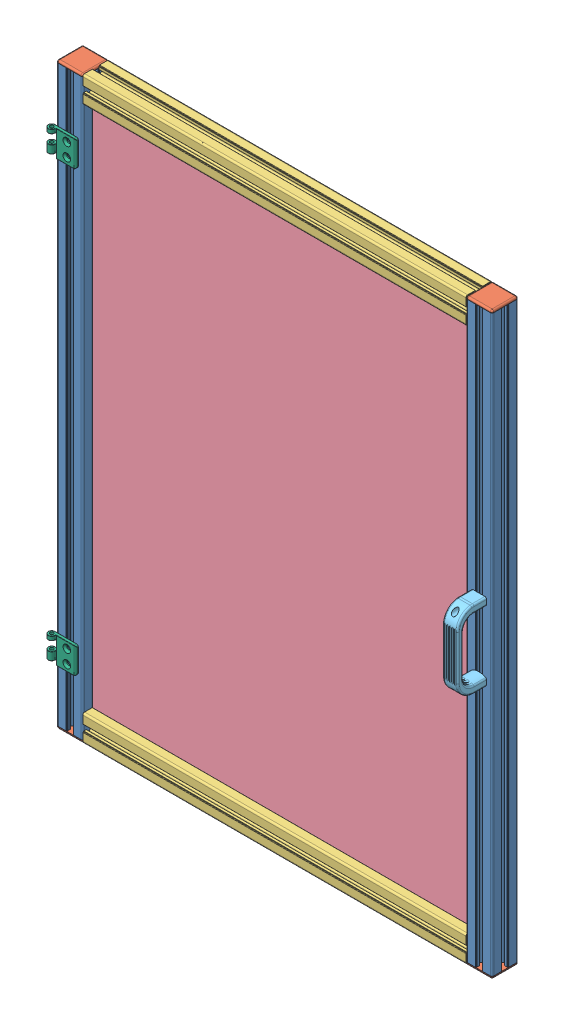
SolidWorks assembly Janela3, configuration Default. Lengths in mm.
Overall size (757.5 996 95.4).
12 component instances, 6 part files, 33 mates.
Components (placement in the parent):
- Perfil45_988-1: Perfil45_988 [Default] at (200.4983 1039.2557 827.0291) x (-1 0 0) z (0 1 0) size (45 45 988)
- Tampa-1: Tampa [Default] at (904.4983 51.2557 827.029) x (1 0 0) z (0 -1 0) size (45.64 46.27 5.14)
- Tampa-2: Tampa [Default] at (904.4983 1039.2557 827.0291) x (1 0 0) z (0 1 0) size (45.64 46.27 5.14)
- Tampa-3: Tampa [Default] at (200.4984 1039.2557 827.0291) x (1 0 0) z (0 1 0) size (45.64 46.27 5.14)
- Tampa-4: Tampa [Default] at (200.4983 51.2557 827.0291) x (1 0 0) z (0 -1 0) size (45.64 46.27 5.14)
- Perfil45_988-2: Perfil45_988 [Default] at (904.4983 51.2557 827.0291) x (1 0 0) z (0 -1 0) size (45 45 988)
- Perfil45_659-1: Perfil45_659 [Default] at (881.9983 1020.7557 827.029) x (0 0 -1) z (1 0 0) size (45 45 659)
- Perfil45_659-2: Perfil45_659 [Default] at (881.9983 69.7557 827.0291) x (0 0 -1) z (1 0 0) size (45 45 659)
- Material_opaco-2: Material_opaco [Default] at (209.5243 77.7557 822.029) size (687 934 5)
- puxador-1: puxador [Default] at (904.4983 486.7557 849.5291) x (0 1 0) z (1 0 0) size (133 49.76 26)
- Rexroth-3 842 535 642_Hinges45-1: Rexroth-3 842 535 642_Hinges45 [Default] at (195.4984 922.7557 852.0291) size (46 45 12)
- Rexroth-3 842 535 642_Hinges45-2: Rexroth-3 842 535 642_Hinges45 [Default] at (195.4984 167.7557 852.0291) size (46 45 12)
Mates (geometry in assembly coordinates):
- Coincident1: coincident anti-aligned: plane of Perfil45_988-1 through (192.7674 51.2557 827.0161) normal (0 -1 0); plane of Tampa-4 through (200.4983 51.2557 827.0291) normal (0 1 0)
- Coincident2: coincident aligned: plane of Perfil45_988-1 through (180.9984 51.2557 849.5291) normal (0 0 1); plane of Tampa-4 through (222.9983 51.2557 849.5291) normal (0 0 1)
- Coincident3: coincident aligned: plane of Perfil45_988-1 through (222.9983 51.2557 833.3291) normal (1 0 0); plane of Tampa-4 through (222.9983 51.2557 804.5291) normal (1 0 0)
- Coincident4: coincident anti-aligned: plane of Tampa-1 through (904.4983 51.2557 827.029) normal (0 1 0); plane of Perfil45_988-2 through (912.2292 51.2557 827.0161) normal (0 -1 0)
- Coincident5: coincident aligned: plane of Tampa-1 through (881.9983 51.2557 804.529) normal (0 0 -1); plane of Perfil45_988-2 through (884.9983 1039.2557 804.529) normal (0 0 -1)
- Coincident6: coincident aligned: plane of Tampa-1 through (881.9983 51.2557 849.529) normal (-1 0 0); plane of Perfil45_988-2 through (881.9983 1039.2557 820.7291) normal (-1 0 0)
- Coincident7: coincident anti-aligned: plane of Perfil45_988-2 through (881.9983 1039.2557 833.3291) normal (-1 0 0); plane of Perfil45_659-2 through (881.9983 69.7427 819.2982) normal (1 0 0)
- Coincident8: coincident aligned: plane of Perfil45_988-2 through (884.9983 1039.2557 849.5291) normal (0 0 1); plane of Perfil45_659-2 through (222.9983 76.0557 849.5291) normal (0 0 1)
- Coincident9: coincident aligned: plane of Tampa-1 through (904.4983 47.2557 827.029) normal (0 -1 0); plane of Perfil45_659-2 through (222.9983 47.2557 846.5291) normal (0 -1 0)
- Coincident10: coincident anti-aligned: plane of Perfil45_988-1 through (222.9983 51.2557 833.3291) normal (1 0 0); plane of Perfil45_659-2 through (222.9983 69.7427 819.2982) normal (-1 0 0)
- Coincident11: coincident aligned: plane of Perfil45_988-1 through (219.9983 51.2557 849.5291) normal (0 0 1); plane of Perfil45_659-2 through (222.9983 76.0557 849.5291) normal (0 0 1)
- Coincident12: coincident aligned: plane of Tampa-4 through (200.4983 47.2557 827.0291) normal (0 -1 0); plane of Perfil45_659-2 through (222.9983 47.2557 846.5291) normal (0 -1 0)
- Coincident13: coincident anti-aligned: plane of Perfil45_988-1 through (192.7674 1039.2557 827.0161) normal (0 1 0); plane of Tampa-3 through (200.4984 1039.2557 827.0291) normal (0 -1 0)
- Coincident14: coincident aligned: plane of Perfil45_988-1 through (180.9984 51.2557 849.5291) normal (0 0 1); plane of Tampa-3 through (177.9984 1039.2557 849.5291) normal (0 0 1)
- Coincident15: coincident aligned: plane of Perfil45_988-1 through (177.9984 51.2557 833.3291) normal (-1 0 0); plane of Tampa-3 through (177.9984 1039.2557 804.5291) normal (-1 0 0)
- Coincident16: coincident anti-aligned: plane of Tampa-2 through (904.4983 1039.2557 827.0291) normal (0 -1 0); plane of Perfil45_988-2 through (912.2292 1039.2557 827.0161) normal (0 1 0)
- Coincident17: coincident aligned: plane of Tampa-2 through (881.9983 1039.2557 849.5291) normal (0 0 1); plane of Perfil45_988-2 through (884.9983 1039.2557 849.5291) normal (0 0 1)
- Coincident18: coincident aligned: plane of Tampa-2 through (881.9983 1039.2557 804.5291) normal (-1 0 0); plane of Perfil45_988-2 through (881.9983 1039.2557 833.3291) normal (-1 0 0)
- Coincident23: coincident anti-aligned: plane of Perfil45_988-1 through (221.2179 51.2557 822.029) normal (0 0 1); plane of Material_opaco-2 through (209.5243 77.7557 822.029) normal (0 0 -1)
- Coincident24: coincident: line of Perfil45_659-2 through (222.9983 77.7557 826.1527) axis (1 0 0); plane of Material_opaco-2 through (209.5243 77.7557 827.029) normal (0 -1 0)
- Coincident25: coincident: line of Perfil45_988-2 through (896.5243 1039.2557 827.8216) axis (0 -1 0); plane of Material_opaco-2 through (896.5243 77.7557 827.029) normal (1 0 0)
- Coincident26: coincident anti-aligned: plane of Perfil45_988-1 through (222.9983 51.2557 833.3291) normal (1 0 0); plane of Perfil45_659-1 through (222.9983 1020.7427 819.2981) normal (-1 0 0)
- Coincident28: coincident aligned: plane of Perfil45_988-1 through (219.9983 51.2557 804.529) normal (0 0 -1); plane of Perfil45_659-1 through (222.9983 1027.0557 804.529) normal (0 0 -1)
- Coincident29: coincident aligned: plane of Tampa-3 through (200.4984 1043.2557 827.0291) normal (0 1 0); plane of Perfil45_659-1 through (222.9983 1043.2557 807.529) normal (0 1 0)
- Width1: width: plane of Perfil45_988-2 through (881.9983 1039.2557 833.3291) normal (-1 0 0); plane of Perfil45_988-2 through (926.9983 1039.2557 833.3291) normal (1 0 0); plane of puxador-1 through (917.4983 478.7557 874.4092) normal (1 0 0); plane of puxador-1 through (891.4983 489.0918 874.4092) normal (-1 0 0)
- Width2: width: plane of Tampa-2 through (904.4983 1043.2557 827.0291) normal (0 1 0); plane of Tampa-1 through (904.4983 47.2557 827.029) normal (0 -1 0); plane of puxador-1 through (891.4983 478.7557 874.4092) normal (0 -1 0); plane of puxador-1 through (891.4983 611.7557 895.9092) normal (0 1 0)
- Coincident30: coincident anti-aligned: plane of Perfil45_988-2 through (923.9983 1039.2557 849.5291) normal (0 0 1); plane of puxador-1 through (904.4983 486.7557 849.5291) normal (0 0 -1)
- Distance1: distance = 98 mm: plane of Tampa-3 through (200.4984 1043.2557 827.0291) normal (0 1 0); plane of Rexroth-3 842 535 642_Hinges45-1 through (175.4984 945.2557 854.5291) normal (0 1 0)
- Distance2: distance = 37.5 mm: plane of Rexroth-3 842 535 642_Hinges45-1 through (215.4984 945.2557 854.5291) normal (1 0 0); plane of Perfil45_988-1 through (177.9984 51.2557 833.3291) normal (-1 0 0)
- Coincident33: coincident anti-aligned: plane of Perfil45_988-1 through (180.9984 51.2557 849.5291) normal (0 0 1); plane of Rexroth-3 842 535 642_Hinges45-1 through (175.4984 900.2557 849.5291) normal (0 0 -1)
- Distance3: distance = 37.5 mm: plane of Rexroth-3 842 535 642_Hinges45-2 through (215.4984 190.2557 854.5291) normal (1 0 0); plane of Perfil45_988-1 through (177.9984 51.2557 833.3291) normal (-1 0 0)
- Distance4: distance = 98 mm: plane of Rexroth-3 842 535 642_Hinges45-2 through (175.4984 145.2557 854.5291) normal (0 -1 0); plane of Tampa-4 through (200.4983 47.2557 827.0291) normal (0 -1 0)
- Coincident36: coincident anti-aligned: plane of Perfil45_988-1 through (180.9984 51.2557 849.5291) normal (0 0 1); plane of Rexroth-3 842 535 642_Hinges45-2 through (175.4984 145.2557 849.5291) normal (0 0 -1)
